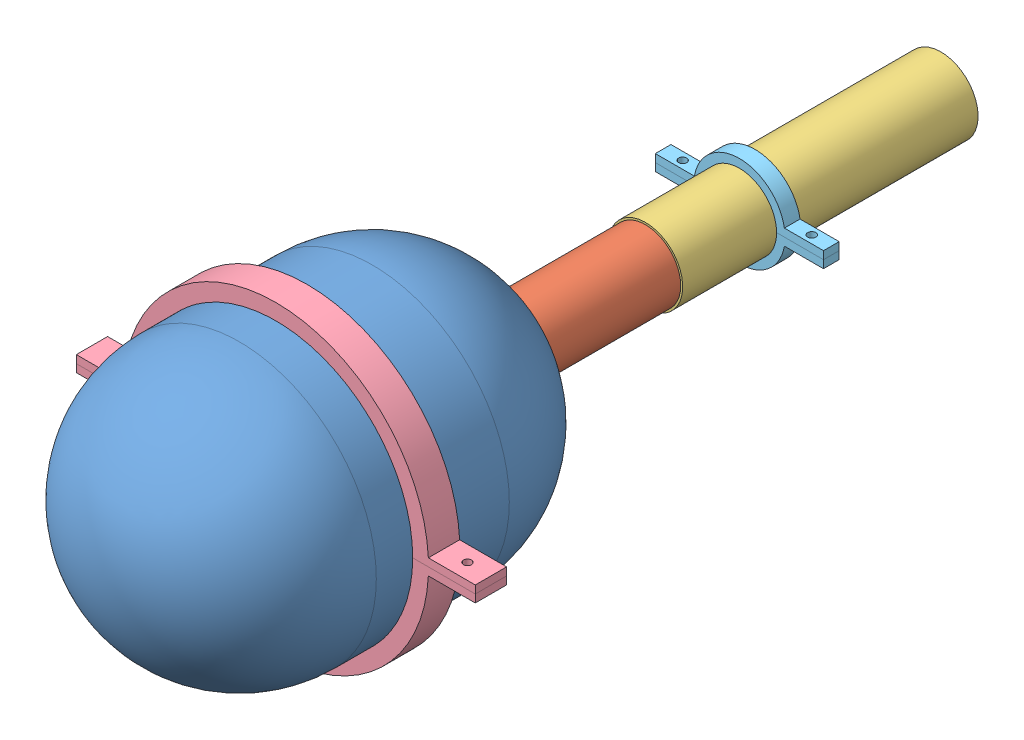
SolidWorks assembly clamping concept, configuration Default. Lengths in mm.
Overall size (161.92 123.99 340.27).
8 component instances, 5 part files, 9 mates.
Components (placement in the parent):
- LoFi Tank+Reg-1: LoFi Tank+Reg [Default] at (68.2452 144.1294 314.9172) size (111.12 111.12 340.27)
  - LoFi Tank-1: LoFi Tank [Default] at origin size (111.12 111.12 163.23)
  - LoFi Reg 1-1: LoFi Reg 1 [Default] at (0 0 -80.6816) x (-0.38598 0.922507 0) z (-0.922507 -0.38598 0) size (28.57 57.15 28.57)
  - LoFi Reg 2-1: LoFi Reg 2 [Default] at (0 0 -137.8316) x (-0.99247 0.12249 0) z (-0.12249 -0.99247 0) size (30.16 119.89 30.16)
- Tank clamp concept 1-1: Tank clamp concept 1 [Default] at (68.2452 144.1294 327.1375) x (1 0 0) z (0 1 0) size (161.93 12.7 61.99)
- Tank clamp concept 1-2: Tank clamp concept 1 [Default] at (68.2452 144.1294 327.1375) x (-1 0 0) z (0 -1 0) size (161.93 12.7 61.99)
- Reg clamp concept 1-1: Reg clamp concept 1 [Default] at (68.2452 144.1294 132.6356) x (1 0 0) z (0 -1 0) size (68.26 6.35 18.53)
- Reg clamp concept 1-2: Reg clamp concept 1 [Default] at (68.2452 144.1294 132.6356) x (-1 0 0) z (0 1 0) size (68.26 6.35 18.53)
Mates (geometry in assembly coordinates):
- Concentric1: concentric anti-aligned: cylinder of LoFi Tank+Reg-1/LoFi Tank-1 through (68.2452 144.1294 234.2356) axis (0 0 -1) radius 55.5625; cylinder of Tank clamp concept 1-1 through (68.2452 144.1294 314.4375) axis (0 0 1) radius 55.5625
- Concentric2: concentric anti-aligned: cylinder of LoFi Tank+Reg-1/LoFi Tank-1 through (68.2452 144.1294 234.2356) axis (0 0 -1) radius 55.5625; cylinder of Tank clamp concept 1-2 through (68.2452 144.1294 314.4375) axis (0 0 1) radius 55.5625
- Perpendicular1: perpendicular: plane of Tank clamp concept 1-2 through (12.6827 144.1294 314.4375) normal (0 -1 0)
- Concentric8: concentric aligned: circle of Tank clamp concept 1-1; circle of Tank clamp concept 1-2
- Concentric3: concentric anti-aligned: cylinder of LoFi Tank+Reg-1/LoFi Reg 2-1 through (68.2452 144.1294 57.1976) axis (0 0 1) radius 15.0812; cylinder of Reg clamp concept 1-1 through (68.2452 144.1294 138.9856) axis (0 0 -1) radius 15.0812
- Perpendicular2: perpendicular: plane of Reg clamp concept 1-1 through (53.1639 144.1294 138.9856) normal (0 -1 0)
- Concentric4: concentric anti-aligned: cylinder of LoFi Tank+Reg-1/LoFi Reg 2-1 through (68.2452 144.1294 57.1976) axis (0 0 1) radius 15.0812; cylinder of Reg clamp concept 1-2 through (68.2452 144.1294 138.9856) axis (0 0 -1) radius 15.0812
- Concentric5: concentric aligned: circle of Reg clamp concept 1-1; circle of Reg clamp concept 1-2
- Distance1: distance = 38.1 mm aligned: plane of Reg clamp concept 1-1 through (68.2452 144.1294 138.9856) normal (0 0 1); plane of LoFi Tank+Reg-1/LoFi Reg 2-1 through (68.2452 144.1294 177.0856) normal (0 0 1)
